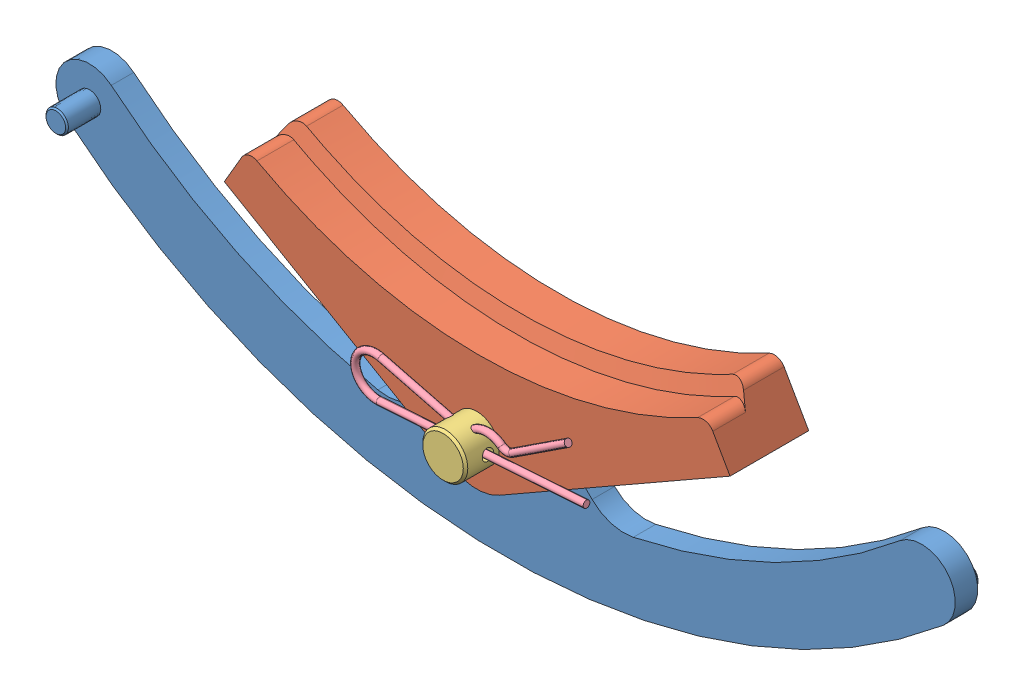
SolidWorks assembly Irisarmclamp, configuration Default. Lengths in mm.
Overall size (160.07 81.81 23).
4 component instances, 4 part files, 5 mates.
Components (placement in the parent):
- Irisarm-1: Irisarm [Default] at origin size (160.07 39 13)
- clampingarc-1: clampingarc [Default] at (45.0713 16.5502 9.125) x (-0.496284 0.86816 0) z (-0.86816 -0.496284 0) size (49.68 14 77.94)
- 93131A320_METRIC CLEVIS PIN-1: 93131A320_METRIC CLEVIS PIN [93131A320] at (0 0 5.125) x (-0.997681 -0.068065 0) z (0 0 -1) size (14 14 23)
- 92375A008_TYPE 316 SS REUSABLE HAIRPIN COTTER PIN-1: 92375A008_TYPE 316 SS REUSABLE HAIRPIN COTTER PIN [92375A008] at (21.5303 1.4689 11.125) x (-0.004946 0.072502 -0.997356) z (0.997681 0.068065 0) size (1.19 9.74 41.27)
Mates (geometry in assembly coordinates):
- Concentric1: concentric anti-aligned: circle of Irisarm-1; circle of clampingarc-1
- Coincident8: coincident anti-aligned: plane of Irisarm-1 through (0 0 0) normal (0 0 -1); plane of clampingarc-1 through (45.0339 7.8071 0) normal (0 0 1)
- Concentric2: concentric aligned: circle of clampingarc-1; circle of 93131A320_METRIC CLEVIS PIN-1
- Coincident10: coincident anti-aligned: plane of clampingarc-1 through (-39.4878 26.2657 -4.875) normal (0 0 -1); plane of 93131A320_METRIC CLEVIS PIN-1 through (0 0 -4.875) normal (0 0 1)
- Concentric3: concentric anti-aligned: cylinder of 93131A320_METRIC CLEVIS PIN-1 through (6.9838 0.4765 11.125) axis (-0.997681 -0.068065 0) radius 1; cylinder of 92375A008_TYPE 316 SS REUSABLE HAIRPIN COTTER PIN-1 through (-15.2935 -1.0434 11.125) axis (0.997681 0.068065 0) radius 0.5953
